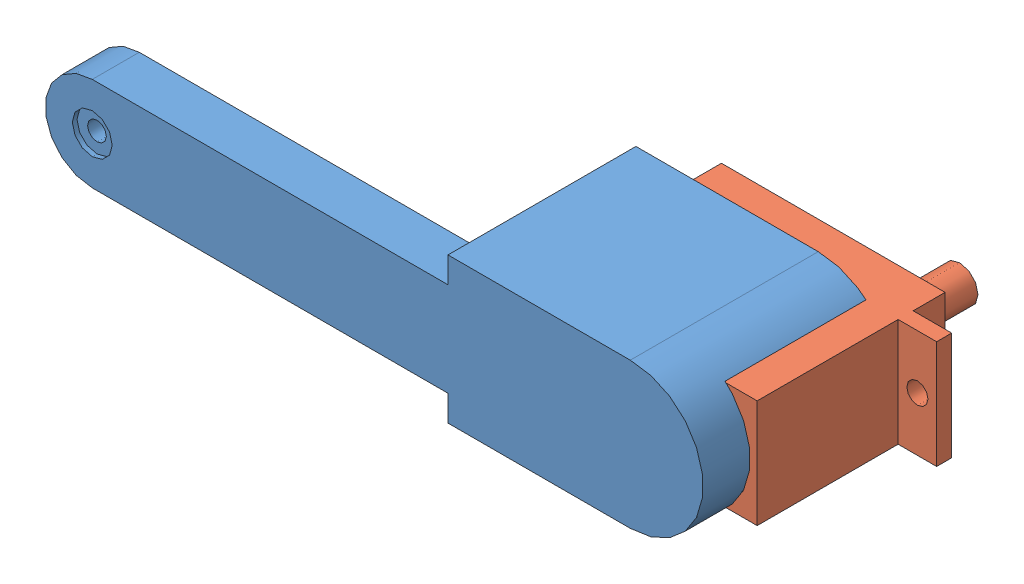
SolidWorks assembly Elbow, configuration Default. Lengths in mm.
Overall size (74.85 15.5 32.3).
2 component instances, 2 part files, 3 mates.
Components (placement in the parent):
- UpperArmLink-1: UpperArmLink [Default] at origin size (70 15.5 20)
- SG90MicroServo-1: SG90MicroServo [Default] at (53.85 0 0) x (1 0 0) z (0 0 -1)
Mates (geometry in assembly coordinates):
- Parallel1: parallel aligned: plane of UpperArmLink-1 through (0 5 5) normal (0 1 0); plane of SG90MicroServo-1 through (41.95 5.75 -20) normal (0 1 0)
- Coincident2: coincident anti-aligned: plane of UpperArmLink-1 through (60 0 0) normal (0 0 -1); plane of SG90MicroServo-1 through (53.85 0 0) normal (0 0 1)
- Concentric2: concentric anti-aligned: line of UpperArmLink-1 through (60 0 5) axis (0 0 -1); cylinder of SG90MicroServo-1 through (60 0 -60.1154) axis (0 0 1) radius 1.95
